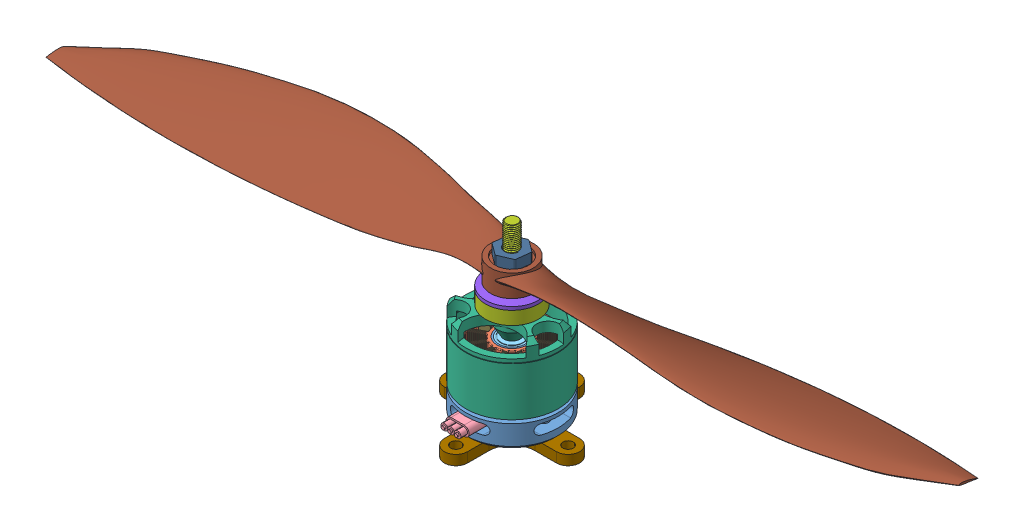
SolidWorks assembly Motor_w_Prop, configuration Default. Lengths in mm.
Overall size (251.81 53.8 89.02).
23 component instances, 11 part files, 32 mates.
Components (placement in the parent):
- Housing_Bottom-1: Housing_Bottom [Default] at origin size (28 20 28)
- Stator-1: Stator [Default] at (0 8 0) size (22 12.2 22)
  - Stator_Steelcore-1: Stator_Steelcore [Default] at origin size (22 12.05 22)
  - Stator_Coil-1: Stator_Coil [Default] at (-2.8504 6 4.9371) x (0.5 0 -0.866025) z (0.866025 0 0.5) size (4.11 12.2 1.21)
  - Stator_Coil-2: Stator_Coil [Default] at (0 6 5.7009) x (0 0 -1) z (1 0 0) size (4.11 12.2 1.21)
  - Stator_Coil-3: Stator_Coil [Default] at (2.8504 6 4.9371) x (-0.5 0 -0.866025) z (0.866025 0 -0.5) size (4.11 12.2 1.21)
  - Stator_Coil-4: Stator_Coil [Default] at (4.9371 6 2.8504) x (-0.866025 0 -0.5) z (0.5 0 -0.866025) size (4.11 12.2 1.21)
  - Stator_Coil-5: Stator_Coil [Default] at (5.7009 6 0) x (-1 0 0) z (0 0 -1) size (4.11 12.2 1.21)
  - Stator_Coil-6: Stator_Coil [Default] at (4.9371 6 -2.8504) x (-0.866025 0 0.5) z (-0.5 0 -0.866025) size (4.11 12.2 1.21)
  - Stator_Coil-7: Stator_Coil [Default] at (2.8504 6 -4.9371) x (-0.5 0 0.866025) z (-0.866025 0 -0.5) size (4.11 12.2 1.21)
  - Stator_Coil-8: Stator_Coil [Default] at (0 6 -5.7009) x (0 0 1) z (-1 0 0) size (4.11 12.2 1.21)
  - Stator_Coil-9: Stator_Coil [Default] at (-2.8504 6 -4.9371) x (0.5 0 0.866025) z (-0.866025 0 0.5) size (4.11 12.2 1.21)
  - Stator_Coil-10: Stator_Coil [Default] at (-4.9371 6 -2.8504) x (0.866025 0 0.5) z (-0.5 0 0.866025) size (4.11 12.2 1.21)
  - Stator_Coil-11: Stator_Coil [Default] at (-5.7009 6 0) size (4.11 12.2 1.21)
  - Stator_Coil-12: Stator_Coil [Default] at (-4.9371 6 2.8504) x (0.866025 0 -0.5) z (0.5 0 0.866025) size (4.11 12.2 1.21)
- Wiring-1: Wiring [Default] at (0.0116 4.5 16.5) x (1 0 0) z (0 0 -1) size (7 3 14.5)
- Rotor-1: Rotor [Default] x (-0.598049 0 0.80146) z (-0.80146 0 -0.598049) size (8 31.7 8)
- Housing_Upper-1: Housing_Upper [Default] at (0 8 0) x (-0.598049 0 0.80146) z (-0.80146 0 -0.598049) size (28 22 28)
- CapScrew-1: CapScrew [Default] at (0 28.5 0) x (0.117196 0 -0.993109) z (0.993109 0 0.117196) size (16 22.3 16)
- Cap-1: Cap [Default] at (0 32.5 0) x (0.117196 0 -0.993109) z (0.993109 0 0.117196) size (16 2 16)
- CrossBase-1: CrossBase [Default] at (0 -3 0) size (41 3 41)
- Nut-1: Nut [Default] at (0 40.4 0) x (0.117196 0 -0.993109) z (0.993109 0 0.117196) size (9.08 3.45 8)
- 1047CCW-1: 1047CCW [Default] at (10.8757 35 -124.5839) x (0.117196 0 -0.993109) z (0.993109 0 0.117196) size (60.56 10.54 246.41)
Mates (geometry in assembly coordinates):
- Concentric1: concentric aligned: cylinder of Stator-1/Stator_Steelcore-1 through (0 20 0) axis (0 -1 0) radius 4.5; cylinder of Housing_Bottom-1 through (0 20 0) axis (0 -1 0) radius 4.5
- Coincident1: coincident aligned: plane of Housing_Bottom-1 through (0 20 0) normal (0 1 0); plane of Stator-1/Stator_Steelcore-1 through (0 20 0) normal (0 1 0)
- Coincident2: coincident anti-aligned: plane of Housing_Bottom-1 through (0 3 0) normal (0 1 0); plane of Wiring-1 through (-1.9884 3 6.5) normal (0 -1 0)
- Lock1: lock: unknown of Housing_Bottom-1; unknown of Wiring-1
- Tangent1: tangent anti-aligned: cylinder of Housing_Bottom-1 through (0 20 0) axis (0 -1 0) radius 4.5; plane of Wiring-1 through (0.0116 4.5 4.5) normal (0 0 -1)
- Coincident6: coincident aligned: plane of Housing_Bottom-1 through (0 20 0) normal (0 1 0); plane of Rotor-1 through (0 20 0) normal (0 1 0)
- Concentric2: concentric aligned: cylinder of Housing_Bottom-1 through (0 14.3137 0) axis (0 -1 0) radius 4; cylinder of Rotor-1 through (0 20 0) axis (0 -1 0) radius 4
- Concentric3: concentric anti-aligned: cylinder of Rotor-1 through (0 30 0) axis (0 -1 0) radius 1.5; cylinder of Housing_Upper-1 through (0 8 0) axis (0 1 0) radius 1.5
- Distance1: distance = 8 mm aligned: plane of Housing_Upper-1; plane of Housing_Bottom-1 through (0 0 0) normal (0 1 0)
- Coincident10: coincident aligned: plane of Housing_Bottom-1 through (0 0 0) normal (0 0 1); plane of Stator-1/Stator_Steelcore-1 through (0 8 0) normal (0 0 1)
- Coincident11: coincident aligned: plane of Rotor-1 through (0 0 0) normal (-0.80146 0 -0.598049); plane of Housing_Upper-1 through (0 8 0) normal (-0.80146 0 -0.598049)
- Coincident12: coincident aligned: plane of Housing_Bottom-1 through (0 0 0) normal (0 0 1); plane of assembly through (0 0 0) normal (0 0 1)
- Coincident13: coincident aligned: plane of Housing_Bottom-1 through (0 0 0) normal (0 1 0); plane of assembly through (0 0 0) normal (0 1 0)
- Coincident14: coincident aligned: plane of Housing_Bottom-1 through (0 0 0) normal (1 0 0); plane of assembly through (0 0 0) normal (1 0 0)
- Concentric4: concentric anti-aligned: cylinder of Housing_Upper-1 through (0 9.9135 0) axis (0 1 0) radius 4.45; cylinder of CapScrew-1 through (0 30 0) axis (0 -1 0) radius 4.5
- Concentric5: concentric aligned: cylinder of Housing_Upper-1 through (-2.3704 28.5 -5.5119) axis (0 1 0) radius 0.625; cylinder of CapScrew-1 through (-2.3704 32.5 -5.5119) axis (0 1 0) radius 0.85
- Concentric6: concentric aligned: cylinder of Housing_Upper-1 through (5.9587 28.5 0.7032) axis (0 1 0) radius 0.625; cylinder of CapScrew-1 through (5.9587 32.5 0.7032) axis (0 1 0) radius 0.85
- Concentric7: concentric aligned: cylinder of Housing_Upper-1 through (-3.5883 28.5 4.8088) axis (0 1 0) radius 0.625; cylinder of CapScrew-1 through (-3.5883 32.5 4.8088) axis (0 1 0) radius 0.85
- Coincident15: coincident anti-aligned: plane of Housing_Upper-1 through (0 28.5 0) normal (0 1 0); plane of CapScrew-1 through (0 28.5 0) normal (0 -1 0)
- Concentric8: concentric anti-aligned: cylinder of CapScrew-1 through (0 50.5 0) axis (0 -1 0) radius 2; cylinder of Cap-1 through (0 32.5 0) axis (0 1 0) radius 2
- Coincident16: coincident anti-aligned: plane of CapScrew-1 through (0 32.5 0) normal (0 1 0); plane of Cap-1 through (0 32.5 0) normal (0 -1 0)
- Concentric19: concentric aligned: cylinder of Housing_Bottom-1 through (0 0 8) axis (0 -1 0) radius 1.6; cylinder of CrossBase-1 through (0 -3 8) axis (0 -1 0) radius 1.6
- Concentric21: concentric aligned: cylinder of Housing_Bottom-1 through (0 0 -8) axis (0 -1 0) radius 1.6; cylinder of CrossBase-1 through (0 -3 -8) axis (0 -1 0) radius 1.6
- Coincident18: coincident anti-aligned: plane of Housing_Bottom-1 through (0 0 0) normal (0 -1 0); plane of CrossBase-1 through (0 0 0) normal (0 1 0)
- Coincident19: coincident aligned: plane of CapScrew-1 through (0 28.5 0) normal (0.993109 0 0.117196); plane of Cap-1 through (0 32.5 0) normal (0.993109 0 0.117196)
- Concentric22: concentric anti-aligned: cylinder of CapScrew-1 through (0 50.5 0) axis (0 -1 0) radius 2; cylinder of Nut-1 through (0 40.4 0) axis (0 1 0) radius 2.25
- Parallel3: parallel aligned: plane of Cap-1 through (0 34.5 0) normal (0 1 0); plane of Nut-1 through (0 43.4 0) normal (0 1 0)
- Concentric23: concentric anti-aligned: cylinder of CapScrew-1 through (0 50.5 0) axis (0 -1 0) radius 2; cylinder of 1047CCW-1 through (0 34.5 0) axis (0 1 0) radius 4
- Coincident21: coincident anti-aligned: plane of Cap-1 through (0 34.5 0) normal (0 1 0); plane of 1047CCW-1 through (0 34.5 0) normal (0 -1 0)
- Coincident22: coincident anti-aligned: plane of Nut-1 through (0 40.4 0) normal (0 -1 0); plane of 1047CCW-1 through (-0.5948 40.4 5.04) normal (0 1 0)
- Parallel4: parallel aligned: plane of Cap-1 through (0 32.5 0) normal (0.993109 0 0.117196); plane of 1047CCW-1 through (10.8757 35 -124.5839) normal (0.993109 0 0.117196)
- Coincident26: coincident aligned: plane of Cap-1 through (0 32.5 0) normal (0.993109 0 0.117196); plane of Nut-1 through (0 40.4 0) normal (0.993109 0 0.117196)
